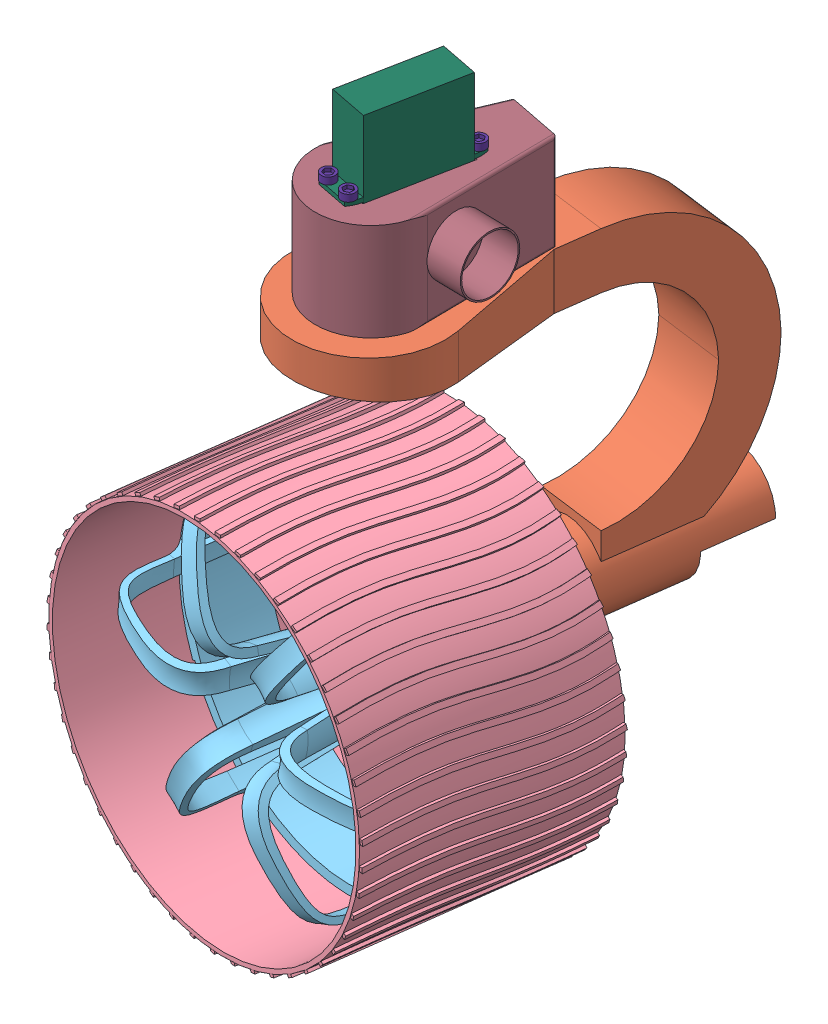
SolidWorks assembly Wheel + connector(right,back), configuration Default. Lengths in mm.
Overall size (185.42 266.57 186.84).
30 component instances, 17 part files, 54 mates.
Components (placement in the parent):
- Wheel motor(RH)-1: Wheel motor(RH) [Default] at (-231.4259 -139.499 43.9631) x (-0.880553 0.459235 -0.117176) z (-0.131908 0 0.991262) size (25 25 73.38)
- Wheel connector(right,front)-1: Wheel connector(right,front) [right frint (mirror)] at (-301.0734 -84.5922 -20.4159) x (0.131908 0 -0.991262) z (0.991262 0 0.131908) size (150.03 127 55.1)
- connector to wheel(RH)-1: connector to wheel(RH) [Default] at (-238.7146 -143.7607 82.0338) x (0.334272 0.941426 0.044482) z (0.131908 0 -0.991262) size (25 25 12.5)
- Wheel-1: Wheel [Default] at (-240.2975 -143.7607 93.929) x (-0.896238 -0.42724 -0.119263) z (-0.131908 0 0.991262) size (132 132 85)
  - Wheel Part-1-1: Wheel Part-1 [Default] at origin size (132 132 85)
  - Wheel Part-2-1: Wheel Part-2 [Default] at (0 0 -2) size (127 128.13 59.75)
- M3 nut-1: M3 nut [Default] at (-243.7631 -141.4002 70.0129) x (-0.975311 -0.178674 -0.129785) z (-0.131908 0 0.991262) size (5 6.35 2.75)
- M3 nut-2: M3 nut [Default] at (-239.5706 -150.3507 70.5708) x (-0.9332 0.337218 -0.124182) z (-0.131908 0 0.991262) size (5 6.35 2.75)
- M3 nut-3: M3 nut [Default] at (-234.8908 -137.1707 71.1935) x (-0.9332 0.337218 -0.124182) z (-0.131908 0 0.991262) size (5 6.35 2.75)
- M3 nut-4: M3 nut [Default] at (-230.6983 -146.1213 71.7514) x (-0.641039 0.762753 -0.085304) z (-0.131908 0 0.991262) size (5 6.35 2.75)
- M3 bolt for wheels(RH)-1: M3 bolt for wheels(RH) [Default] at (-242.5385 -150.3507 92.8742) x (-0.915656 -0.383049 -0.121847) z (0.131908 0 -0.991262) size (5 5 25.25)
- M3 bolt for wheels(RH)-2: M3 bolt for wheels(RH) [Default] at (-233.6662 -146.1213 94.0548) x (-0.915656 -0.383049 -0.121847) z (0.131908 0 -0.991262) size (5 5 25.25)
- M3 bolt for wheels(RH)-3: M3 bolt for wheels(RH) [Default] at (-237.8587 -137.1707 93.4969) x (-0.915656 -0.383049 -0.121847) z (0.131908 0 -0.991262) size (5 5 25.25)
- M3 bolt for wheels(RH)-4: M3 bolt for wheels(RH) [Default] at (-246.731 -141.4002 92.3163) x (-0.915656 -0.383049 -0.121847) z (0.131908 0 -0.991262) size (5 5 25.25)
- Washer(M6)-1: Washer(M6) [Default] at (-237.0258 -27.559 85.0059) size (8.76 0.5 8.76)
- double row cylindrical roller bearing_is-1: double row cylindrical roller bearing_is [IS 6458 DC - 49-6-S] at (-237.0258 -22.059 85.0059) x (0.284513 0 -0.958672) z (0 -1 0) size (15 15 10)
- Steering thor joint(RH)-1: Steering thor joint(RH) [Default] at (-268.7978 -18.7982 89.0856) x (-0.465586 0 0.885003) z (0 1 0) size (14.13 14.13 58.56)
  - bolt head(RH)-1: bolt head(RH) [Default] at (-18.4031 26.2188 19.7392) size (14 14 8)
  - Bogie bolt(RH)-1: Bogie bolt(RH) [Default] at (-18.4064 26.2246 14.7392) x (-1 0 0) z (0 0 -1) size (9 10.39 55.56)
  - Bolt servo connector(RH)-1: Bolt servo connector(RH) [Default] at (-18.4031 26.2188 19.7392) x (0.99996 0.008969 0) z (0 0 1) size (14 14 3)
- Steering connector(right,back)-1: Steering connector(right,back) [Default] at (-237.0258 -27.059 85.0059) x (0.191589 0 -0.981475) z (0.981475 0 0.191589) size (70 36.07 51.58)
- Servo Assembly-1: Servo Assembly [Default] at (-235.1099 4.941 75.1911) x (0.981475 0 0.191589) z (-0.191589 0 0.981475) size (14 33 44) (flexible)
  - servo shaft-1: servo shaft [Default] at (0 -3 10) x (0.994486 0 0.104866) z (-0.104866 0 0.994486) size (5 18 5)
  - Servo motor-1: Servo motor [Default] at origin size (14 30 44)
- Bogie nut(RH)-1: Bogie nut(RH) [Default] at (-237.0258 -41.6423 85.0059) x (0.924412 0 -0.381395) z (0.381395 0 0.924412) size (8.33 4.53 10.58)
- Bogie nut(RH)-2: Bogie nut(RH) [Default] at (-237.0258 -45.809 85.0059) size (8.33 4.53 10.58)
- M3 bolt-1: M3 bolt [Default] at (-243.4093 10.691 93.9587) x (-0.934722 0 0.355379) z (0 -1 0) size (5 5 12.17)
- M3 bolt-2: M3 bolt [Default] at (-234.4779 10.691 95.7022) x (-0.998535 0 -0.054114) z (0 -1 0) size (5 5 12.17)
- M3 bolt-3: M3 bolt [Default] at (-235.742 10.691 54.6801) x (0.752526 0 -0.658562) z (0 -1 0) size (5 5 12.17)
- M3 bolt-4: M3 bolt [Default] at (-226.8105 10.691 56.4235) x (0.208857 0 0.977946) z (0 -1 0) size (5 5 12.17)
Mates (geometry in assembly coordinates):
- Concentric21: concentric: cylinder of Wheel motor(RH)-1 through (-238.7146 -143.7607 82.0338) axis (0.131908 0 -0.991262) radius 2.0271; cylinder of connector to wheel(RH)-1 through (-238.7148 -143.7607 82.0348) axis (0.131908 0 -0.991262) radius 2.025
- Coincident1: coincident: axis of connector to wheel(RH)-1 through (-245.247 -141.4002 81.1646) axis (0.131908 0 -0.991262); axis of M3 nut-1 through (-243.8211 -141.4002 70.4487) axis (-0.131908 0 0.991262)
- Coincident2: coincident: axis of connector to wheel(RH)-1 through (-241.0545 -150.3507 81.7225) axis (0.131908 0 -0.991262); axis of M3 nut-2 through (-239.6286 -150.3507 71.0066) axis (-0.131908 0 0.991262)
- Coincident3: coincident: axis of connector to wheel(RH)-1 through (-236.3747 -137.1707 82.3452) axis (0.131908 0 -0.991262); axis of M3 nut-3 through (-234.9347 -137.1707 71.5238) axis (-0.131908 0 0.991262)
- Coincident4: coincident: axis of connector to wheel(RH)-1 through (-232.1822 -146.1213 82.9031) axis (0.131908 0 -0.991262); axis of M3 nut-4 through (-230.7422 -146.1213 72.0817) axis (-0.131908 0 0.991262)
- Coincident5: coincident: plane of connector to wheel(RH)-1 through (-237.3956 -143.7607 72.1212) normal (0.131908 0 -0.991262); plane of M3 nut-1 through (-243.928 -141.4002 71.252) normal (-0.131908 0 0.991262)
- Parallel1: parallel: plane of connector to wheel(RH)-1 through (-240.8698 -144.3972 71.6589) normal (-0.975311 -0.178674 -0.129785); plane of M3 nut-1 through (-241.234 -142.3737 71.6104) normal (0.975311 0.178674 0.129785)
- Parallel2: parallel: plane of connector to wheel(RH)-1 through (-239.7286 -142.9177 71.8108) normal (0.9332 -0.337218 0.124182); plane of M3 nut-2 through (-241.586 -148.1488 71.5636) normal (-0.9332 0.337218 -0.124182)
- Coincident7: coincident: plane of connector to wheel(RH)-1 through (-237.3956 -143.7607 72.1212) normal (0.131908 0 -0.991262); plane of M3 nut-2 through (-239.7355 -150.3507 71.8099) normal (-0.131908 0 0.991262)
- Coincident8: coincident: plane of connector to wheel(RH)-1 through (-233.9213 -143.1243 72.5835) normal (0.975311 0.178674 0.129785); plane of M3 nut-4 through (-233.5571 -145.1478 72.632) normal (-0.975311 -0.178674 -0.129785)
- Coincident9: coincident: plane of connector to wheel(RH)-1 through (-237.3956 -143.7607 72.1212) normal (0.131908 0 -0.991262); plane of M3 nut-4 through (-230.8631 -146.1213 72.9905) normal (-0.131908 0 0.991262)
- Parallel3: parallel: plane of connector to wheel(RH)-1 through (-238.912 -135.3363 71.9194) normal (0.177112 -0.983908 0.023568); plane of M3 nut-3 through (-236.0206 -139.8884 72.3042) normal (0.177112 -0.983908 0.023568)
- Coincident10: coincident: plane of connector to wheel(RH)-1 through (-237.3956 -143.7607 72.1212) normal (0.131908 0 -0.991262); plane of M3 nut-3 through (-235.0556 -137.1707 72.4326) normal (-0.131908 0 0.991262)
- Coincident11: coincident: axis of Wheel motor(RH)-1 through (-238.6968 -143.7607 81.8999) axis (0.131908 0 -0.991262); axis of Wheel-1/Wheel Part-1-1 through (-245.9036 -143.7607 136.0576) axis (0.131908 0 -0.991262)
- Coincident13: coincident: plane of connector to wheel(RH)-1 through (-238.7146 -143.7607 82.0338) normal (-0.131908 0 0.991262); plane of Wheel-1/Wheel Part-2-1 through (-238.7146 -143.7607 82.0338) normal (0.131908 0 -0.991262)
- Concentric22: concentric: cylinder of connector to wheel(RH)-1 through (-232.1824 -146.1213 82.9041) axis (0.131908 0 -0.991262) radius 1.71; cylinder of Wheel-1/Wheel Part-2-1 through (-238.5803 -146.1213 130.9833) axis (0.131908 0 -0.991262) radius 1.71
- Coincident14: coincident: axis of Wheel-1/Wheel Part-2-1 through (-242.3736 -150.3507 91.6351) axis (0.131908 0 -0.991262); axis of M3 bolt for wheels(RH)-1 through (-239.4057 -150.3507 69.3317) axis (-0.131908 0 0.991262)
- Coincident15: coincident: plane of Wheel-1/Wheel Part-2-1 through (-242.3736 -150.3507 91.6351) normal (-0.131908 0 0.991262); plane of M3 bolt for wheels(RH)-1 through (-242.3736 -150.3507 91.6351) normal (0.131908 0 -0.991262)
- Coincident16: coincident: axis of Wheel-1/Wheel Part-2-1 through (-233.5013 -146.1213 92.8157) axis (0.131908 0 -0.991262); axis of M3 bolt for wheels(RH)-2 through (-230.5334 -146.1213 70.5123) axis (-0.131908 0 0.991262)
- Coincident17: coincident: plane of Wheel-1/Wheel Part-2-1 through (-240.0337 -143.7607 91.9465) normal (-0.131908 0 0.991262); plane of M3 bolt for wheels(RH)-2 through (-233.5013 -146.1213 92.8157) normal (0.131908 0 -0.991262)
- Coincident18: coincident: axis of Wheel-1/Wheel Part-2-1 through (-246.5661 -141.4002 91.0772) axis (0.131908 0 -0.991262); axis of M3 bolt for wheels(RH)-4 through (-243.5982 -141.4002 68.7738) axis (-0.131908 0 0.991262)
- Coincident19: coincident: plane of Wheel-1/Wheel Part-2-1 through (-246.5661 -141.4002 91.0772) normal (-0.131908 0 0.991262); plane of M3 bolt for wheels(RH)-4 through (-246.5661 -141.4002 91.0772) normal (0.131908 0 -0.991262)
- Coincident20: coincident: axis of Wheel-1/Wheel Part-2-1 through (-237.6938 -137.1707 92.2578) axis (0.131908 0 -0.991262); axis of M3 bolt for wheels(RH)-3 through (-234.7259 -137.1707 69.9544) axis (-0.131908 0 0.991262)
- Coincident21: coincident: plane of Wheel-1/Wheel Part-2-1 through (-237.6938 -137.1707 92.2578) normal (-0.131908 0 0.991262); plane of M3 bolt for wheels(RH)-3 through (-237.6938 -137.1707 92.2578) normal (0.131908 0 -0.991262)
- Coincident22: coincident: plane of Wheel motor(RH)-1 through (-236.5615 -139.5591 82.3204) normal (-0.131908 0 0.991262); plane of connector to wheel(RH)-1 through (-238.7146 -143.7607 82.0338) normal (-0.131908 0 0.991262)
- Coincident24: coincident: plane of Washer(M6)-1 through (-237.0258 -27.059 85.0059) normal (0 1 0); plane of double row cylindrical roller bearing_is-1 through (-234.1498 -27.059 85.8594) normal (0 -1 0)
- Concentric25: concentric: cylinder of Washer(M6)-1 through (-237.0258 -27.059 85.0059) axis (0 -1 0) radius 3; cylinder of double row cylindrical roller bearing_is-1 through (-237.0258 -92.9216 85.0059) axis (0 -1 0) radius 3
- Coincident28: coincident: plane of double row cylindrical roller bearing_is-1 through (-229.8358 -27.059 87.1397) normal (0 -1 0); plane of Steering connector(right,back)-1 through (-237.0258 -27.059 85.0059) normal (0 -1 0)
- Concentric29: concentric: cylinder of Steering thor joint(RH)-1/bolt head(RH)-1 through (-237.0258 -6.059 85.0059) axis (0 1 0) radius 7; cylinder of Steering connector(right,back)-1 through (-237.0258 8.4751 85.0059) axis (0 -1 0) radius 3
- Coincident29: coincident: plane of Steering thor joint(RH)-1/bolt head(RH)-1 through (-237.0258 -7.059 85.0059) normal (0 -1 0); plane of Steering connector(right,back)-1 through (-237.0258 -7.059 85.0059) normal (0 1 0)
- Parallel4: parallel: plane of Steering connector(right,back)-1 through (-231.1017 -7.059 93.8039) normal (-0.981475 0 -0.191589); plane of Servo Assembly-1/Servo motor-1 through (-228.2396 34.941 76.5322) normal (0.981475 0 0.191589)
- Concentric31: concentric: cylinder of Steering thor joint(RH)-1/Bolt servo connector(RH)-1 through (-237.0258 3.941 85.0059) axis (0 -1 0) radius 2.5; cylinder of Servo Assembly-1/servo shaft-1 through (-237.0258 19.941 85.0059) axis (0 -1 0) radius 2.5
- Coincident30: coincident: plane of Steering thor joint(RH)-1/Bolt servo connector(RH)-1 through (-237.0258 1.941 85.0059) normal (0 1 0); plane of Servo Assembly-1/servo shaft-1 through (-237.0258 1.941 85.0059) normal (0 -1 0)
- Coincident31: coincident: plane of Steering connector(right,back)-1 through (-237.0258 7.941 85.0059) normal (0 1 0); plane of Servo Assembly-1/Servo motor-1 through (-235.1099 7.941 75.1911) normal (0 -1 0)
- Concentric32: concentric: cylinder of double row cylindrical roller bearing_is-1 through (-237.0258 -72.4506 85.0059) axis (0 -1 0) radius 7.5; cylinder of Steering connector(right,back)-1 through (-237.0258 -17.059 85.0059) axis (0 -1 0) radius 7.5
- Concentric33: concentric: cylinder of Wheel connector(right,front)-1 through (-237.0258 -51.559 85.0059) axis (0 1 0) radius 3; cylinder of Steering connector(right,back)-1 through (-237.0258 -17.059 85.0059) axis (0 -1 0) radius 7.5
- Coincident33: coincident: plane of Wheel connector(right,front)-1 through (-236.6414 -27.559 -11.8419) normal (0 1 0); plane of Washer(M6)-1 through (-237.0258 -27.559 85.0059) normal (0 -1 0)
- Concentric34: concentric: cylinder of Wheel motor(RH)-1 through (-233.326 -139.5591 58.0068) axis (0.131908 0 -0.991262) radius 12.5004; cylinder of Wheel connector(right,front)-1 through (-233.8875 -139.559 62.2265) axis (0.131908 0 -0.991262) radius 12.5
- Concentric35: concentric: cylinder of Wheel motor(RH)-1 through (-238.7146 -143.7607 82.0338) axis (0.131908 0 -0.991262) radius 2.0271; cylinder of Wheel connector(right,front)-1 through (-223.0279 -143.7607 -35.8492) axis (-0.131908 0 0.991262) radius 2.435
- LimitAngle1: limit planar angle = 0.060487 rad: plane of Wheel connector(right,front)-1 through (-221.3563 -139.559 -31.9434) normal (0.131908 0 -0.991262); plane of Steering connector(right,back)-1 through (-237.2612 7.941 34.0162) normal (0.191589 0 -0.981475)
- Coincident36: coincident: axis of Bogie nut(RH)-1 through (-237.0258 -39.559 85.0059) axis (0 -1 0); axis of Bogie nut(RH)-2 through (-237.0258 -43.7257 85.0059) axis (0 -1 0)
- Concentric36: concentric: cylinder of Steering connector(right,back)-1 through (-237.0258 -17.059 85.0059) axis (0 -1 0) radius 7.5; axis of Bogie nut(RH)-1 through (-237.0258 -41.0664 85.0059) axis (0 1 0)
- Parallel6: parallel: plane of Wheel connector(right,front)-1 through (-232.2566 -49.559 85.6405) normal (-0.792504 0 -0.609867); plane of Bogie nut(RH)-1 through (-235.1908 -39.559 89.4535) normal (0.792504 0 0.609867)
- Coincident37: coincident: plane of Wheel connector(right,front)-1 through (-211.8598 -39.559 -8.5442) normal (0 -1 0); plane of Bogie nut(RH)-1 through (-237.0258 -39.559 85.0059) normal (0 1 0)
- Coincident38: coincident: plane of Bogie nut(RH)-1 through (-237.0258 -43.7257 85.0059) normal (0 -1 0); plane of Bogie nut(RH)-2 through (-237.0258 -43.7257 85.0059) normal (0 1 0)
- Coincident39: coincident: plane of Wheel motor(RH)-1 through (-233.8876 -139.5591 62.2265) normal (-0.131908 0 0.991262); plane of Wheel connector(right,front)-1 through (-221.4967 -84.5922 63.8754) normal (0.131908 0 -0.991262)
- Concentric37: concentric: cylinder of Servo Assembly-1/Servo motor-1 through (-243.4093 9.441 93.9587) axis (0 -1 0) radius 1.5; cylinder of M3 bolt-1 through (-243.4093 9.441 93.9587) axis (0 1 0) radius 2.5
- Concentric38: concentric: cylinder of Servo Assembly-1/Servo motor-1 through (-234.4779 9.441 95.7022) axis (0 -1 0) radius 1.5; cylinder of M3 bolt-2 through (-234.4779 9.441 95.7022) axis (0 1 0) radius 2.5
- Concentric39: concentric: cylinder of Servo Assembly-1/Servo motor-1 through (-235.742 9.441 54.6801) axis (0 -1 0) radius 1.5; cylinder of M3 bolt-3 through (-235.742 9.441 54.6801) axis (0 1 0) radius 2.5
- Concentric40: concentric: cylinder of Servo Assembly-1/Servo motor-1 through (-226.8105 9.441 56.4235) axis (0 -1 0) radius 1.5; cylinder of M3 bolt-4 through (-226.8105 9.441 56.4235) axis (0 1 0) radius 2.5
- Coincident40: coincident: plane of Servo Assembly-1/Servo motor-1 through (-235.1099 9.441 75.1911) normal (0 1 0); plane of M3 bolt-4 through (-226.8105 9.441 56.4235) normal (0 -1 0)
- Coincident41: coincident: plane of Servo Assembly-1/Servo motor-1 through (-235.1099 9.441 75.1911) normal (0 1 0); plane of M3 bolt-3 through (-235.742 9.441 54.6801) normal (0 -1 0)
- Coincident42: coincident: plane of Servo Assembly-1/Servo motor-1 through (-235.1099 9.441 75.1911) normal (0 1 0); plane of M3 bolt-1 through (-243.4093 9.441 93.9587) normal (0 -1 0)
- Coincident43: coincident: plane of Servo Assembly-1/Servo motor-1 through (-235.1099 9.441 75.1911) normal (0 1 0); plane of M3 bolt-2 through (-234.4779 9.441 95.7022) normal (0 -1 0)
